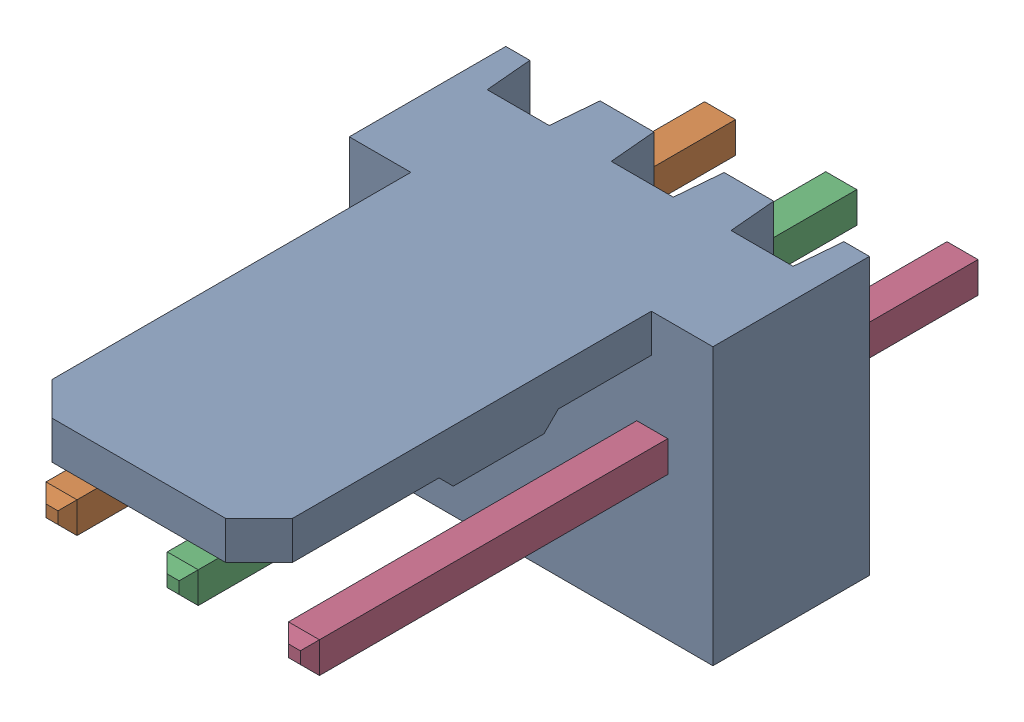
SolidWorks assembly Molex PCB 3 pin v2 v6 (1), configuration Default. Lengths in mm.
Overall size (7.62 5.79 14.92).
4 component instances, 2 part files, 0 mates.
Components (placement in the parent):
- BASE9710016 (1)-1: BASE9710016 (1) [Default] at (2.54 2.895 -8.22) size (7.62 5.79 11.5)
- PINO9710016 (1)-1: PINO9710016 (1) [Default] at (1.27 3.325 -0.72) size (0.65 0.65 14.2)
- PINO9710016 (1)-2: PINO9710016 (1) [Default] at (3.81 3.325 -0.72) size (0.65 0.65 14.2)
- PINO9710016 (1)-3: PINO9710016 (1) [Default] at (6.35 3.325 -0.72) size (0.65 0.65 14.2)
